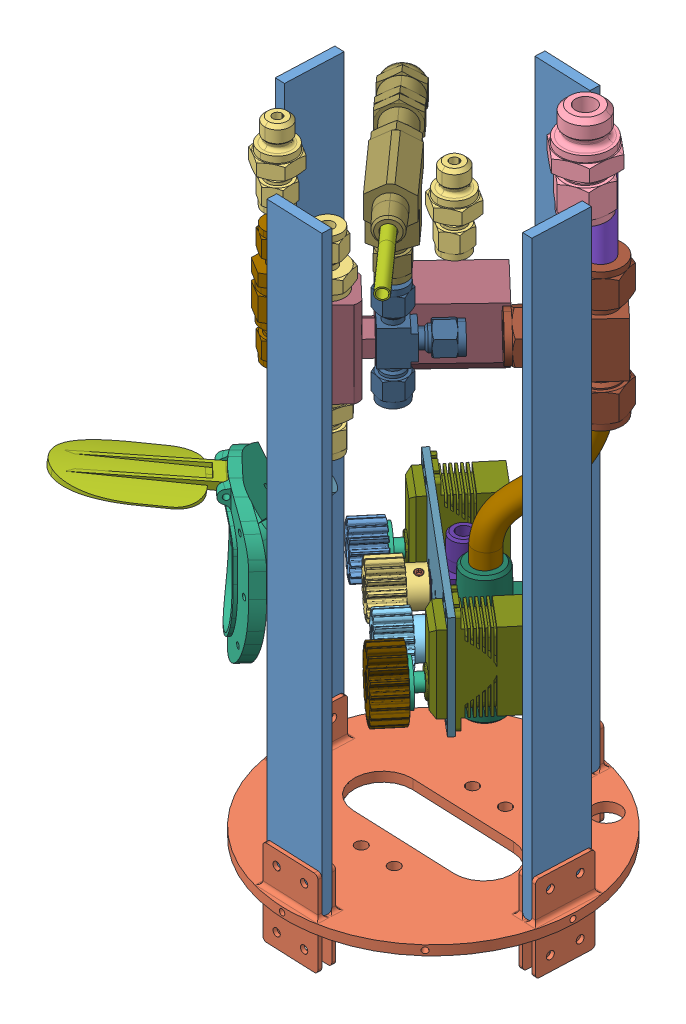
SolidWorks assembly 133000_Valves_bay, configuration Défaut. Lengths in mm.
Overall size (212.63 353.56 215.74).
47 component instances, 28 part files, 15 mates.
Components (placement in the parent):
- 115200_Valve_Bay-1: 115200_Valve_Bay [Défaut] at (-12.4539 17.9089 -8.6926) x (0.999191 0 0.040223) z (-0.040223 0 0.999191) size (152.4 335 152.4)
  - 115204_Rod-1: 115204_Rod [Valve_Bay] at (209.7958 298.5461 -253.845) x (1 0 0) z (0 -1 0) size (30 5 310)
  - 115101_Thrust_Plate-1: 115101_Thrust_Plate [Défaut] at (209.7958 -16.4539 -313.845) size (152.4 45 152.4)
  - 115204_Rod-2: 115204_Rod [Valve_Bay] at (149.7958 298.5461 -313.845) x (0 0 1) z (0 -1 0) size (30 5 310)
  - 115204_Rod-3: 115204_Rod [Valve_Bay] at (209.7958 298.5461 -373.845) x (-1 0 0) z (0 -1 0) size (30 5 310)
  - 115204_Rod-4: 115204_Rod [Valve_Bay] at (269.7958 298.5461 -313.845) x (0 0 -1) z (0 -1 0) size (30 5 310)
- 133003_raccord_SW_G_4_SS-400-1-4RP-1: 133003_raccord_SW_G_4_SS-400-1-4RP [Défaut] at (173.6527 292.5954 -268.3772) x (0 1 0) z (0 0 1) size (40.39 19.05 22)
- 133003_raccord_SW_G_4_SS-400-1-4RP-2: 133003_raccord_SW_G_4_SS-400-1-4RP [Défaut] at (232.2805 284.5954 -302.3667) x (0 1 0) z (0 0 1) size (40.39 19.05 22)
- 133004_raccord_SW_G_8_SS-400-1-4RP-1: 133004_raccord_SW_G_8_SS-400-1-4RP [Défaut] at (251.105 287.5154 -352.1161) x (0 1 0) z (-0.934249 0 0.356622) size (47.5 26.99 31.16)
- 133008_embout_remplissage-1: 133008_embout_remplissage [Défaut] at (332.9885 29.2294 -446.2871) x (-0.725859 0 -0.687844) z (0.405405 0.807852 -0.42781) size (63.65 135.28 112.81)
  - 236100SA_FILLING_LINE_R01.CATProduct-1: 236100SA_FILLING_LINE_R01.CATProduct [Défaut] at origin size (63.65 135.28 112.81)
    - 236109_SS-TH4TA4TA4-8.CATPart-1: 236109_SS-TH4TA4TA4-8.CATPart [Défaut] at (-1.679 261.5706 -36.5068) x (0 -0.15448 0.987996) z (-0.859917 -0.504306 -0.078852) size (41.66 13.72 13.72) (hidden)
    - 236106_SS-QF4-S-400.CATPart-1: 236106_SS-QF4-S-400.CATPart [Défaut] at (-1.679 259.0593 -20.4459) x (0 0.15448 -0.987996) z (0.999559 0.029342 0.004588) size (44.96 14.3 16.5)
    - 236130_QUICK_FITTING_HOLDER_R05.CATPart-1: 236130_QUICK_FITTING_HOLDER_R05.CATPart [Défaut] at (-1.679 250.22 36.0872) x (-1 0 0) z (0 0.807852 -0.589385) size (63.65 82.68 39.71)
    - 236131_COVER_R01.CATPart-1: 236131_COVER_R01.CATPart [Défaut] at (-1.9173 218.291 -89.0139) x (-1 0 0) z (0 0.470072 0.882628) size (39.54 69.43 6.01)
    - COMPRESSIVE_JOINT.CATPart-1: COMPRESSIVE_JOINT.CATPart [Défaut] at (-1.679 261.806 -38.0125) x (0 -0.15448 0.987996) z (-0.987996 0.152625 0.023864) size (0.5 16 16)
- 133002_check_valve_SS-CHS4-25-1: 133002_check_valve_SS-CHS4-25 [Défaut] at (173.6527 222.9008 -268.3772) x (0 1 0) z (-0.020209 0 0.999796) size (61.72 17.46 20.16)
- 133001_raccord_T_4_SS-400-3-1: 133001_raccord_T_4_SS-400-3 [Défaut] at (201.839 256.9232 -300.7041) x (0 -1 0) z (-0.680479 0 0.732767) size (53.85 14.22 35.14)
- 133007_raccord_T_8_SS_810_3-1: 133007_raccord_T_8_SS_810_3 [Défaut] at (254.1552 193.9312 -357.0404) x (0 1 0) z (0.680479 0 -0.732767) size (72.14 22.35 48.97)
- 133005_pressure_relief_4_SS-4R3A1-2: 133005_pressure_relief_4_SS-4R3A1 [Défaut] at (201.839 299.9006 -300.7041) x (0 -1 0) z (-0.665365 0 -0.746518) size (51.64 20.24 98.81)
- 133006_soleno_quart-1: 133006_soleno_quart [Défaut] at (210.5044 188.9676 -236.7593) x (0.723246 0 0.69059) z (0 1 0) size (28 80.02 47.02)
- 133003_raccord_SW_G_4_SS-400-1-4RP-3: 133003_raccord_SW_G_4_SS-400-1-4RP [Défaut] at (165.7236 160.5196 -302.5493) x (0 1 0) z (0.271213 0 -0.962519) size (40.39 19.05 22)
- 133003_raccord_SW_G_4_SS-400-1-4RP-4: 133003_raccord_SW_G_4_SS-400-1-4RP [Défaut] at (165.7236 262.4156 -302.5493) x (0 -1 0) z (0.697628 0 -0.71646) size (40.39 19.05 22)
- 135000_systeme_servo-1: 135000_systeme_servo [Défaut] at (220.9337 1.9612 -308.7023) x (-0.766044 0 -0.642788) z (0 1 0) size (115.02 63.08 70.73)
  - support vanne servo-1: support vanne servo [Défaut] at (11.6117 -0.2898 118.0217) size (110 3 54)
  - SS-8P6T2-SwagelokCompany-3D-11-16-2022-1: SS-8P6T2-SwagelokCompany-3D-11-16-2022 [Défaut] at (-2.7383 -31.2778 99.9999) x (0 0 1) z (0 1 0) size (67.06 28.45 46.75)
  - Savox_SB2290SG Servo.stp-1: Savox_SB2290SG Servo.stp [Défaut] at (-30.1883 -2.5398 110) x (0 0 1) z (0 1 0) size (54 20.2 42.6)
  - SS-4P4T2-SwagelokCompany-3D-11-16-2022-1: SS-4P4T2-SwagelokCompany-3D-11-16-2022 [Défaut] at (30.8117 -21.3718 99.9999) x (0 0 1) z (0 1 0) size (48.26 18.8 31.12)
  - Savox_SB2290SG Servo.stp-3: Savox_SB2290SG Servo.stp [Défaut] at (55.6117 -2.5398 110.2) x (0 0 1) z (0 1 0) size (54 20.2 42.6)
  - GEAB1.5-20-15-B-10 v1.step-1: GEAB1.5-20-15-B-10 v1.step [Défaut] at (-30.1884 31.7992 99.9999) x (1 0 0) z (0 -1 0) size (33 33 15.01)
    - GEAB1.5-20-15-B-10_b.step-1: GEAB1.5-20-15-B-10_b.step [Défaut] at origin size (33 33 15.01)
  - GEAB1.5-15-15-B-10 v0.step-1: GEAB1.5-15-15-B-10 v0.step [Défaut] at (55.6116 16.3713 100.1999) x (1 0 0) z (0 1 0) size (25.44 25.39 15.01)
    - GEAB1.5-15-15-B-10_b.step-1: GEAB1.5-15-15-B-10_b.step [Défaut] at origin size (25.44 25.39 15.01)
  - GEAB1.5-15-15-B-10.stp-1: GEAB1.5-15-15-B-10.stp [Défaut] at (30.8117 27.2102 99.9999) x (0.94768 0 0.319221) z (0 -1 0) size (25.44 25.39 24.01)
    - SET-SCREW4-4.stp-1: SET-SCREW4-4.stp [Défaut] at (0 5 20) x (0 -1 0) z (-1 0 0) size (4 4 4)
    - GEAB1.5-15-15-B-10_b.stp-1: GEAB1.5-15-15-B-10_b.stp [Défaut] at origin size (25.44 25.39 24.01)
  - GEAB1.5-15-15-B-12.stp-1: GEAB1.5-15-15-B-12.stp [Défaut] at (-2.7383 27.2102 99.9999) x (0.774557 0 -0.632504) z (0 -1 0) size (25.44 25.39 24.01)
    - SET-SCREW4-3.stp-1: SET-SCREW4-3.stp [Défaut] at (0 6 20) x (0 -1 0) z (-1 0 0) size (3 4 4)
    - GEAB1.5-15-15-B-12_b.stp-1: GEAB1.5-15-15-B-12_b.stp [Défaut] at origin size (25.44 25.39 24.01)
  - raccord servo v2.step-1: raccord servo v2.step [Défaut] at (65.6117 16.7992 100.1999) x (1 0 0) z (0 -1 0) size (21 21 7)
  - raccord servo v2.step-2: raccord servo v2.step [Défaut] at (-20.1883 16.7992 99.9999) x (1 0 0) z (0 -1 0) size (21 21 7)
- 133101_tuyau_droit_4-1: 133101_tuyau_droit_4 [50] at (173.6527 266.7771 -268.3772) x (-0.448364 0 0.893851) z (-0.893851 0 -0.448364) size (6.35 30 6.35)
- 133101_tuyau_droit_4-2: 133101_tuyau_droit_4 [50] at (201.839 239.9281 -300.7041) x (0.795427 0 0.60605) z (-0.60605 0 0.795427) size (6.35 30 6.35)
- 133103_tuyau_droit_8-1: 133103_tuyau_droit_8 [Défaut] at (254.1552 254.3505 -357.0404) x (0.959047 0 0.283248) z (-0.283248 0 0.959047) size (12.7 50 12.7)
- 133101_tuyau_droit_4-3: 133101_tuyau_droit_4 [50] at (208.6963 299.9006 -293.0104) x (-0.51985 -0.717687 0.463337) z (-0.535766 0.696366 0.477523) size (6.35 30 6.35)
- 133101_tuyau_droit_4-4: 133101_tuyau_droit_4 [50] at (228.6572 299.9006 -270.6148) x (0.423755 -0.823275 -0.377689) z (-0.61459 -0.567642 0.547778) size (6.35 30 6.35)
- 133102_tuyau_courbe_8-1: 133102_tuyau_courbe_8 [Défaut] at (244.5949 163.3311 -340.4446) x (-0.499166 0 0.866506) z (-0.866506 0 -0.499166) size (56.73 88.44 12.7)
Mates (geometry in assembly coordinates):
- Coaxiale9: concentric anti-aligned: cylinder of 122003_raccord_SW_G_4_SS-400-1-4RP-1 through (173.6527 300.2154 -268.3772) axis (0 1 0) radius 3.175; cylinder of 122002_check_valve_SS-CHS4-25-1 through (173.6527 277.0028 -268.3772) axis (0 -1 0) radius 3.175
- Coaxiale15: concentric anti-aligned: cylinder of 122001_raccord_T_4_SS-400-3-1 through (201.839 249.3032 -300.7041) axis (0 -1 0) radius 3.175; cylinder of 122005_pressure_relief_4_SS-4R3A1-2 through (201.839 266.8806 -300.7041) axis (0 1 0) radius 3.175
- Coaxiale16: concentric anti-aligned: cylinder of 122006_soleno_quart-1 through (165.7236 188.9676 -302.5493) axis (0 -1 0) radius 3.3782; cylinder of 122003_raccord_SW_G_4_SS-400-1-4RP-4 through (165.7236 226.8713 -302.5493) axis (0 1 0) radius 6.5785
- Coaxiale21: concentric aligned: cylinder of 122006_soleno_quart-1 through (165.7236 188.9676 -302.5493) axis (0 -1 0) radius 3.3782; cylinder of 122003_raccord_SW_G_4_SS-400-1-4RP-3 through (165.7236 196.064 -302.5493) axis (0 -1 0) radius 6.5785
- Coïncidente9: coincident anti-aligned: plane of 122006_soleno_quart-1 through (210.5044 188.9676 -236.7593) normal (0 -1 0); plane of 122003_raccord_SW_G_4_SS-400-1-4RP-3 through (165.7236 188.9676 -302.5493) normal (0 1 0)
- Coaxiale22: concentric aligned: cylinder of 122006_soleno_quart-1 through (165.7236 188.9676 -302.5493) axis (0 -1 0) radius 3.3782; cylinder of 122003_raccord_SW_G_4_SS-400-1-4RP-4 through (165.7236 227.9986 -302.5493) axis (0 -1 0) radius 2.413
- Coïncidente10: coincident anti-aligned: plane of 122006_soleno_quart-1 through (210.5044 233.9676 -236.7593) normal (0 1 0); plane of 122003_raccord_SW_G_4_SS-400-1-4RP-4 through (165.7236 233.9676 -302.5493) normal (0 -1 0)
- Coaxiale26: concentric anti-aligned: cylinder of 122001_raccord_T_4_SS-400-3-1 through (214.9749 229.9992 -314.8494) axis (-0.680479 0 0.732767) radius 3.175; cylinder of 122007_raccord_T_8_SS_810_3-1 through (237.3896 229.9992 -338.9864) axis (0.680479 0 -0.732767) radius 6.35
- Coaxiale29: concentric aligned: cylinder of 122002_check_valve_SS-CHS4-25-1 through (173.6527 277.0028 -268.3772) axis (0 -1 0) radius 3.175; cylinder of 122101_tuyau_droit_4-1 through (173.6527 296.7771 -268.3772) axis (0 -1 0) radius 3.175
- Coaxiale30: concentric aligned: cylinder of 122001_raccord_T_4_SS-400-3-1 through (201.839 249.3032 -300.7041) axis (0 -1 0) radius 3.175; cylinder of 122101_tuyau_droit_4-2 through (201.839 269.9281 -300.7041) axis (0 -1 0) radius 2.5
- Coaxiale31: concentric aligned: cylinder of 122007_raccord_T_8_SS_810_3-1 through (254.1552 254.6372 -357.0404) axis (0 -1 0) radius 6.35; cylinder of 122101_tuyau_droit_8-1 through (254.1552 304.3505 -357.0404) axis (0 -1 0) radius 5
- Coaxiale32: concentric anti-aligned: cylinder of 122005_pressure_relief_4_SS-4R3A1-2 through (216.9258 299.9006 -283.7771) axis (0.665365 0 0.746518) radius 3.556; cylinder of 122101_tuyau_droit_4-3 through (228.6572 299.9006 -270.6148) axis (-0.665365 0 -0.746518) radius 3.175
- Coaxiale33: concentric aligned: cylinder of 122101_tuyau_droit_4-3 through (228.6572 299.9006 -270.6148) axis (-0.665365 0 -0.746518) radius 2.5; cylinder of 122101_tuyau_droit_4-4 through (248.6182 299.9006 -248.2193) axis (-0.665365 0 -0.746518) radius 2.5
- Coïncidente12: coincident anti-aligned: plane of 122101_tuyau_droit_4-3 through (228.6572 299.9006 -270.6148) normal (0.665365 0 0.746518); plane of 122101_tuyau_droit_4-4 through (228.6572 299.9006 -270.6148) normal (-0.665365 0 -0.746518)
- Coaxiale35: concentric aligned: cylinder of 122007_raccord_T_8_SS_810_3-1 through (254.1552 205.3612 -357.0404) axis (0 1 0) radius 6.35; cylinder of 122102_tuyau_courbe_8-1 through (254.1552 201.3395 -357.0404) axis (0 1 0) radius 5
